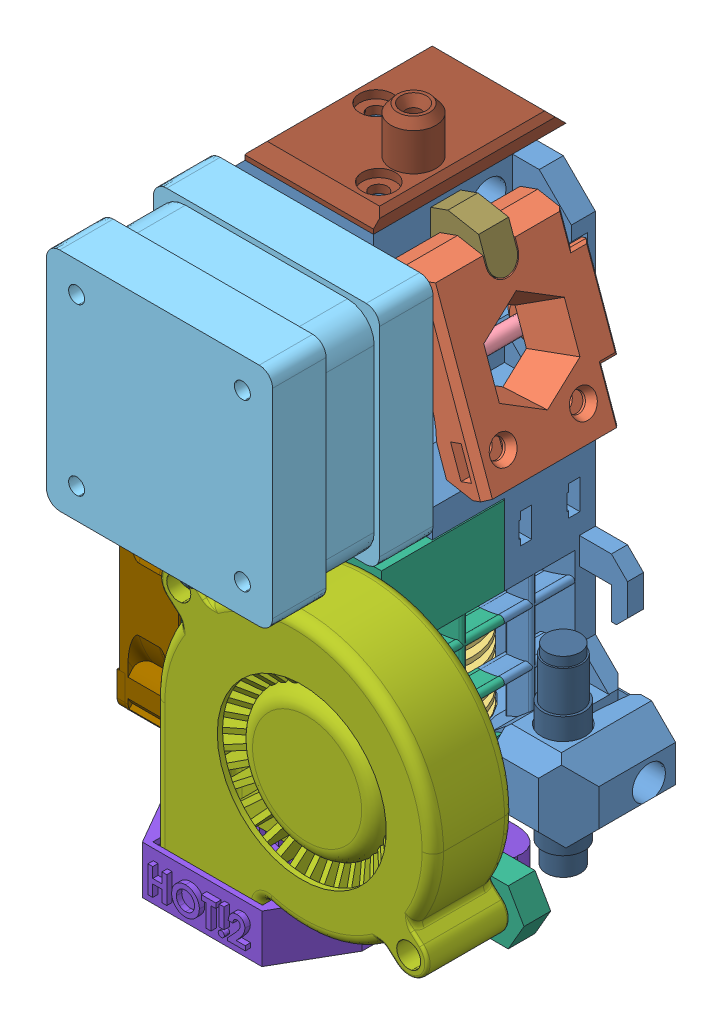
SolidWorks assembly Extruder Assembly, configuration Default. Lengths in mm.
Overall size (76.41 114.5 66).
12 component instances, 12 part files, 29 mates.
Components (placement in the parent):
- extruder-body-1: extruder-body [Default] at (24.1066 59.0375 55.4042) x (-1 0 0) z (0 0 -1) size (63.5 95 30.5)
- extruder-idler-1: extruder-idler [Default] at (39.0743 57.6459 53.9042) x (0 0 -1) z (0.941715 0.336411 0) size (28 34 17)
- E3D V6-1: E3D V6 [Default] at (24.1066 48.6175 72.4042) x (1 0 0) z (0 -1 0) size (21.69 25.84 58.6)
- idler pulley shaft-1: idler pulley shaft [Default] at (33.7581 84.4179 56.6542) x (-0.93241 -0.361403 0) z (0 0 1) size (3 3 24)
- MOTOR_NEMA17_30MM-1: MOTOR_NEMA17_30MM [Default] at (20.1066 86.0375 100.9042) x (0 -1 0) z (0 0 -1) size (54.71 42.3 52)
- extruder-cover-1: extruder-cover [Default] at (24.1066 59.0375 55.4042) x (-1 0 0) z (0 0 -1) size (75.15 49.75 23.94)
- FAN_5015_BLOWER-1: FAN_5015_BLOWER [Default] at (41.6066 38.5375 110.8042) x (0 -1 0) z (1 0 0) size (51.75 17.19 52.1)
- nozzle-fan-1: nozzle-fan [Default] at (24.1066 59.0375 59.9042) x (-1 0 0) z (0 0 -1) size (47.83 17 42)
- Noctua-NF-A4x10-1: Noctua-NF-A4x10 [Default] at (-2.3925 37.472 75.3387) x (0 0 -1) z (-1 0 0) size (40.06 40.06 12.26)
- PINDA Probe-1: PINDA Probe [Default] at (47.1066 30.9837 67.4042) x (0.998123 0 0.061245) z (0 -1 0) size (7.8 7.8 35.75)
- filament-sensor-cover-1: filament-sensor-cover [Default] at (24.1066 59.0375 55.4042) x (-1 0 0) z (0 0 -1) size (24 11.5 36)
- extruder-idler-plug-1: extruder-idler-plug [Default] at (39.0743 57.6459 53.9042) x (-0.941715 -0.336411 0) z (0 0 -1) size (10.6 10.3 5.6)
Mates (geometry in assembly coordinates):
- Concentric1: concentric aligned: cylinder of extruder-body-1 through (35.6066 101.5375 58.1042) axis (0 0 -1) radius 3.1; cylinder of extruder-idler-1 through (35.6066 101.5375 85.9042) axis (0 0 -1) radius 1.7
- Concentric2: concentric aligned: cylinder of extruder-body-1 through (24.1066 63.0375 72.4042) axis (0 -1 0) radius 6.05; cylinder of E3D V6-1 through (24.1066 48.6175 72.4042) axis (0 -1 0) radius 5.95
- Distance1: distance = 1.7 mm anti-aligned: plane of E3D V6-1 through (16.2066 61.2375 72.4042) normal (0 -1 0); plane of extruder-body-1 through (24.1066 59.5375 72.4042) normal (0 1 0)
- Parallel1: parallel aligned: plane of extruder-body-1 through (3.6066 56.5375 80.4042) normal (-1 0 0); plane of E3D V6-1 through (16.6066 8.4175 77.4042) normal (-1 0 0)
- Concentric3: concentric aligned: cylinder of extruder-idler-1 through (33.7581 84.4179 85.9042) axis (0 0 -1) radius 1.5; cylinder of idler pulley shaft-1 through (33.7581 84.4179 80.6542) axis (0 0 -1) radius 1.5
- Coincident1: coincident aligned: plane of extruder-idler-1 through (23.3992 80.7173 80.6542) normal (0 0 1); plane of idler pulley shaft-1 through (33.7581 84.4179 80.6542) normal (0 0 1)
- Concentric5: concentric aligned: cylinder of extruder-body-1 through (35.6066 70.5375 95.4042) axis (0 0 -1) radius 1.7; cylinder of MOTOR_NEMA17_30MM-1 through (35.6066 70.5375 85.9042) axis (0 0 -1) radius 1.5
- Concentric6: concentric aligned: cylinder of extruder-body-1 through (4.6066 70.5375 95.4042) axis (0 0 -1) radius 1.7; cylinder of MOTOR_NEMA17_30MM-1 through (4.6066 70.5375 85.9042) axis (0 0 -1) radius 1.5
- Coincident2: coincident anti-aligned: plane of extruder-body-1 through (41.1066 22.5375 85.9042) normal (0 0 1); plane of MOTOR_NEMA17_30MM-1 through (20.1066 86.0375 85.9042) normal (0 0 -1)
- Coincident3: coincident anti-aligned: plane of extruder-body-1 through (42.1066 20.0375 72.4042) normal (0 0 1); plane of extruder-cover-1 through (41.1066 22.5375 72.4042) normal (0 0 -1)
- Concentric7: concentric aligned: cylinder of E3D V6-1 through (24.1066 48.6175 72.4042) axis (0 -1 0) radius 5.95; cylinder of extruder-cover-1 through (24.1066 63.0375 72.4042) axis (0 -1 0) radius 6.05
- Coincident4: coincident aligned: plane of extruder-body-1 through (34.1066 24.0375 95.9542) normal (0 1 0); plane of extruder-cover-1 through (41.3066 24.0375 91.4042) normal (0 1 0)
- Coincident6: coincident anti-aligned: plane of extruder-cover-1 through (41.1066 22.5375 95.4042) normal (0 0 1); plane of FAN_5015_BLOWER-1 through (41.6066 38.5375 95.4042) normal (0 0 -1)
- Parallel3: parallel aligned: plane of extruder-cover-1 through (8.6066 15.0375 95.4042) normal (0 -1 0); plane of FAN_5015_BLOWER-1 through (34.2066 12.8375 110.8042) normal (0 -1 0)
- Coincident7: coincident anti-aligned: plane of extruder-cover-1 through (41.1066 22.5375 95.4042) normal (0 0 1); plane of nozzle-fan-1 through (13.6066 6.0375 95.4042) normal (0 0 -1)
- Concentric11: concentric aligned: circle of extruder-cover-1; circle of nozzle-fan-1
- Parallel4: parallel anti-aligned: plane of extruder-cover-1 through (8.6066 15.0375 95.4042) normal (0 -1 0); plane of nozzle-fan-1 through (13.6066 23.0375 100.4042) normal (0 1 0)
- Concentric13: concentric anti-aligned: circle of extruder-cover-1; cylinder of FAN_5015_BLOWER-1 through (18.6066 58.5375 110.8042) axis (0 0 -1) radius 2.25
- Coincident8: coincident anti-aligned: plane of extruder-cover-1 through (3.6066 21.5375 96.4042) normal (-1 0 0); plane of Noctua-NF-A4x10-1 through (3.6066 55.4999 93.3666) normal (1 0 0)
- Concentric17: concentric anti-aligned: cylinder of extruder-cover-1 through (17.1066 53.5375 91.4042) axis (-1 0 0) radius 1.4; cylinder of Noctua-NF-A4x10-1 through (-7.8916 53.5375 91.4042) axis (1 0 0) radius 2.159
- Parallel5: parallel aligned: plane of extruder-body-1 through (8.6066 15.0375 72.4042) normal (0 -1 0); plane of Noctua-NF-A4x10-1 through (-7.8916 17.4441 93.3666) normal (0 -1 0)
- Concentric18: concentric anti-aligned: cylinder of extruder-body-1 through (47.1066 54.0375 67.4042) axis (0 -1 0) radius 4.1; cylinder of PINDA Probe-1 through (47.1066 45.0027 67.4042) axis (0 1 0) radius 3.9
- Coincident9: coincident aligned: plane of E3D V6-1 through (24.1066 6.4175 72.4042) normal (0 -1 0); plane of PINDA Probe-1 through (47.1066 6.4175 67.4042) normal (0 -1 0)
- Coincident10: coincident anti-aligned: plane of extruder-body-1 through (41.1066 109.0375 85.9042) normal (0 1 0); plane of filament-sensor-cover-1 through (30.1066 109.0375 85.9042) normal (0 -1 0)
- Concentric19: concentric aligned: cylinder of extruder-body-1 through (24.1066 109.5375 72.4042) axis (0 -1 0) radius 2.1; cylinder of filament-sensor-cover-1 through (24.1066 118.8375 72.4042) axis (0 -1 0) radius 2.2
- Concentric20: concentric aligned: cone of extruder-body-1 through (25.1066 109.0375 79.9042) axis (0 -1 0); cylinder of filament-sensor-cover-1 through (25.1066 113.5375 79.9042) axis (0 -1 0) radius 3.1
- Distance2: distance = 0.5 mm anti-aligned: plane of extruder-idler-1 through (51.0465 74.6655 60.4042) normal (0 0 -1); plane of extruder-body-1 through (50.1066 88.0375 59.9042) normal (0 0 1)
- Concentric21: concentric: cylinder of extruder-idler-1 through (35.6066 101.5375 85.9042) axis (0 0 -1) radius 1.7; cylinder of extruder-idler-plug-1 through (35.6066 101.5375 85.711) axis (0 0 -1) radius 1.5
- Concentric22: concentric aligned: cylinder of extruder-idler-1 through (43.443 104.8679 72.4042) axis (-0.941715 -0.336411 0) radius 3; cylinder of extruder-idler-plug-1 through (40.6178 103.8586 72.4042) axis (-0.941715 -0.336411 0) radius 2.8
